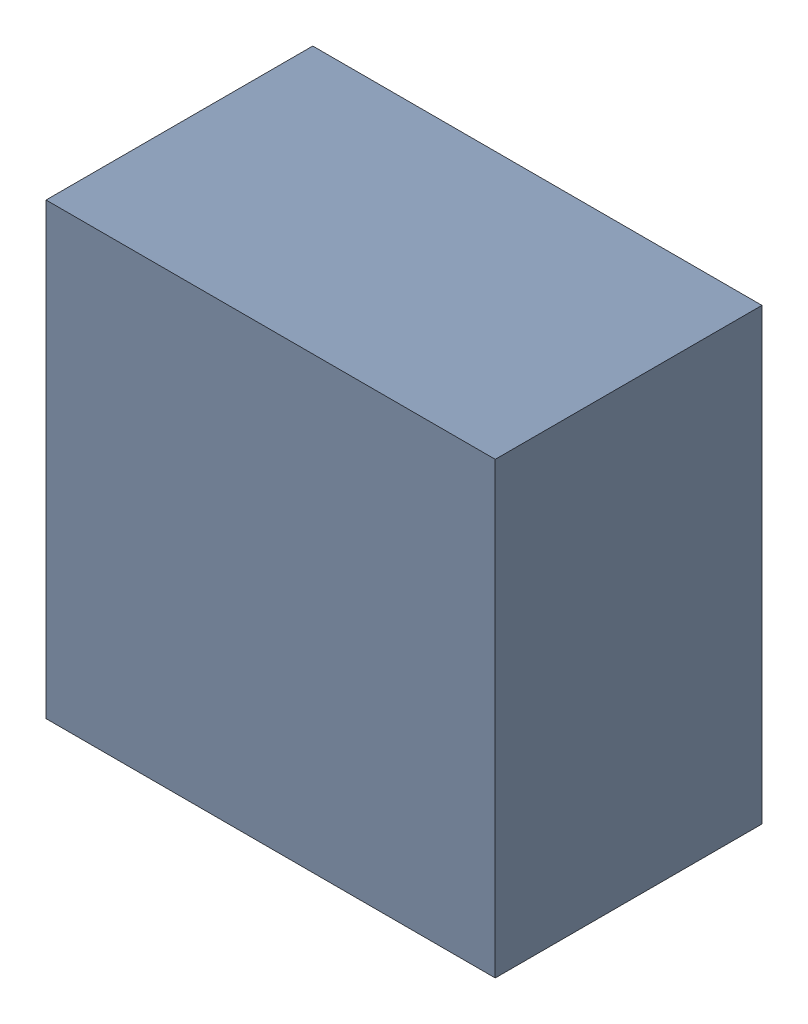
SolidWorks assembly U1, configuration Default. Lengths in mm.
Overall size (12.19 12.19 7.24).
2 component instances, 1 part files, 0 mates.
Components (placement in the parent):
- 580494096-1: 580494096 [Default] at (212.724 101.728 0) size (12.19 12.19 7.24)
  - Extruded_2-1: Extruded_2 [Default] at origin size (12.19 12.19 7.24)
